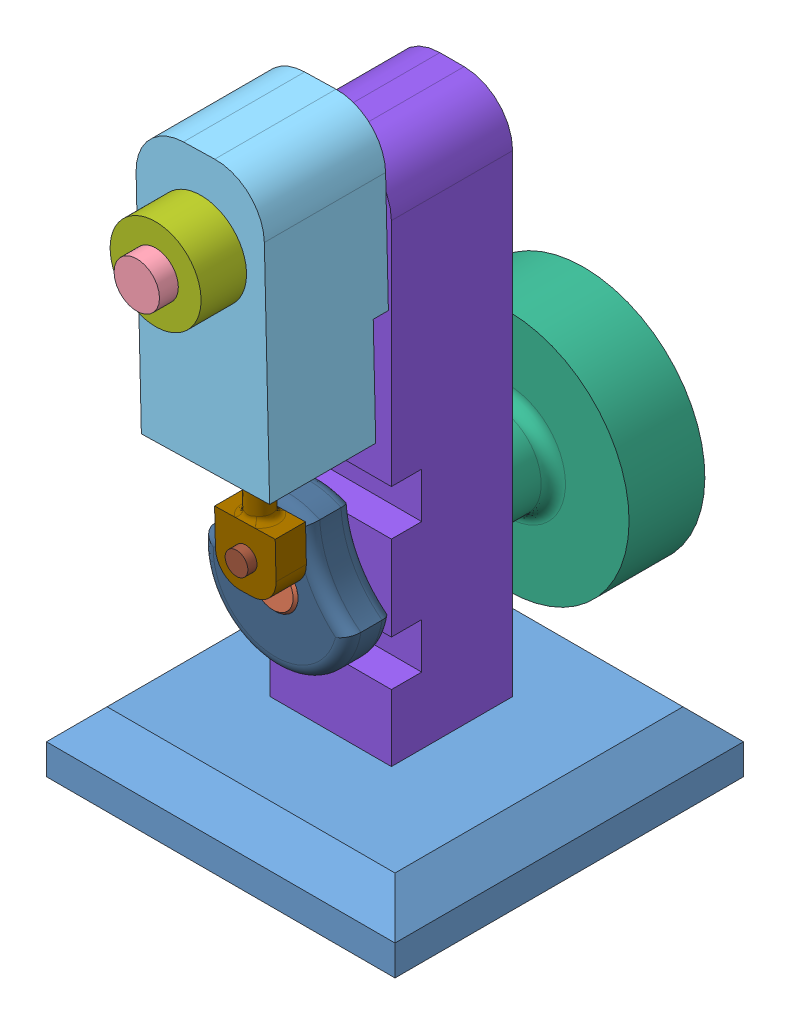
SolidWorks assembly Piston, configuration Default. Lengths in mm.
Overall size (2875 5329.59 4587.69).
11 component instances, 11 part files, 20 mates.
Components (placement in the parent):
- Part1_Base-1: Part1_Base [Default] at (2749.9801 1228.0338 658.172) size (2875 500 2875)
- Part1_Big Bar-1: Part1_Big Bar [Default] at (1225.0249 3003.0338 3015.4848) x (-0.109858 0.993947 0) z (-0.993947 -0.109858 0) size (375 2563 375)
- Part1_Bolt-1: Part1_Bolt [Default] at (1225.0249 1115.6147 2037.9848) x (0.905293 0 -0.424787) z (0.424787 0 0.905293) size (375 750 375)
- Part1_Connecting Bolt-1: Part1_Connecting Bolt [Default] at (1406.6994 5671.6591 4137.9848) x (0.824835 0.565374 0) z (-0.565374 0.824835 0) size (375 2250 375)
- Part1_Cylinder-1: Part1_Cylinder [Default] at (1649.1321 5484.5228 3607.9848) x (-0.999724 -0.023506 0) z (0.023506 -0.999724 0) size (1058.3 1000 2250)
- Part1_Fly Wheel-1: Part1_Fly Wheel [Default] at (1225.0249 3003.0338 452.4848) x (0.993947 0.109858 0) z (0.109858 -0.993947 0) size (2000 1000 2000)
- Part1_Holder-1: Part1_Holder [Default] at (1225.0249 5718.0338 3982.9848) x (0.933124 0.359555 0) z (0 0 1) size (750 750 500)
- Part1_Main Body-1: Part1_Main Body [Default] at (1725.0249 2291.4623 2303.3643) x (0 -0.473688 0.880693) z (0 -0.880693 -0.473688) size (2917.55 1000 4260.67)
- Part1_Piston-1: Part1_Piston [Default] at (1243.0245 4952.5149 3170.4848) x (0 0 -1) z (-0.999724 -0.023506 0) size (500 1835 500)
- Part1_Shaft Wheel-1: Part1_Shaft Wheel [Default] at (1225.0249 3003.0338 2620.4848) x (0.990355 -0.138553 0) z (-0.138553 -0.990355 0) size (1236.29 388.31 1222.98)
- Part1_Small Bar-1: Part1_Small Bar [Default] at (1280.1407 3373.9751 3370.4848) x (0.000458 1 0) z (-1 0.000458 0) size (187.5 750 187.5)
Mates (geometry in assembly coordinates):
- Coincident1: coincident: circle of Part1_Base-1; circle of Part1_Main Body-1
- Parallel1: parallel: line of Part1_Base-1 through (2499.9801 1728.0338 3283.172) axis (0 0 -1); line of Part1_Main Body-1 through (1725.0249 1728.0338 1537.9848) axis (0 0 1)
- Concentric1: concentric: cylinder of Part1_Big Bar-1 through (1225.0249 3003.0338 452.4848) axis (0 0 1) radius 187.5; cylinder of Part1_Main Body-1 through (1225.0249 3003.0338 -126.54) axis (0 0 1) radius 187.5
- Concentric2: concentric: cylinder of Part1_Big Bar-1 through (1225.0249 3003.0338 452.4848) axis (0 0 1) radius 187.5; cylinder of Part1_Fly Wheel-1 through (1225.0249 3003.0338 577.4848) axis (0 0 1) radius 187.5
- Parallel2: parallel: plane of Part1_Big Bar-1 through (1254.1239 3194.8918 577.4848) normal (-0.993947 -0.109858 0); plane of Part1_Fly Wheel-1 through (1272.8214 3008.3166 577.4848) normal (0.993947 0.109858 0)
- Coincident4: coincident: plane of Part1_Big Bar-1 through (1225.0249 3003.0338 452.4848) normal (0 0 -1); plane of Part1_Fly Wheel-1 through (1225.0249 3003.0338 452.4848) normal (0 0 -1)
- Concentric3: concentric: cylinder of Part1_Big Bar-1 through (1225.0249 3003.0338 452.4848) axis (0 0 1) radius 187.5; cylinder of Part1_Shaft Wheel-1 through (1225.0249 3003.0338 2995.4848) axis (0 0 -1) radius 187.5
- Concentric4: concentric: cylinder of Part1_Shaft Wheel-1 through (876.2224 2865.2948 2995.4848) axis (0 0 -1) radius 93.5; cylinder of Part1_Small Bar-1 through (876.2224 2865.2948 2620.4848) axis (0 0 1) radius 93.75
- Coincident6: coincident: plane of Part1_Shaft Wheel-1 through (1225.0249 3003.0338 2620.4848) normal (0 0 -1); plane of Part1_Small Bar-1 through (876.2224 2865.2948 2620.4848) normal (0 0 -1)
- Concentric5: concentric: cylinder of Part1_Piston-1 through (876.2224 2865.2948 2920.4838) axis (0 0 1) radius 93.5; cylinder of Part1_Small Bar-1 through (876.2224 2865.2948 2620.4848) axis (0 0 1) radius 93.75
- Distance1: distance = 50 mm: plane of Part1_Piston-1 through (1036.0864 3118.1675 3045.4848) normal (0 0 -1); plane of Part1_Shaft Wheel-1 through (1225.0249 3003.0338 2995.4848) normal (0 0 1)
- Coincident8: coincident: circle of Part1_Big Bar-1; plane of Part1_Shaft Wheel-1 through (1225.0249 3003.0338 2995.4848) normal (0 0 1)
- Concentric6: concentric: cylinder of Part1_Connecting Bolt-1 through (1225.0249 5718.0338 1887.9848) axis (0 0 1) radius 187.5; cylinder of Part1_Main Body-1 through (1225.0249 5718.0338 1887.9848) axis (0 0 1) radius 187.5
- Coincident9: coincident: plane of Part1_Connecting Bolt-1 through (1225.0249 5718.0338 1887.9848) normal (0 0 -1); plane of Part1_Main Body-1 through (1225.0249 5718.0338 1887.9848) normal (0 0 1)
- Concentric7: concentric: cylinder of Part1_Connecting Bolt-1 through (1225.0249 5718.0338 1887.9848) axis (0 0 1) radius 187.5; cylinder of Part1_Cylinder-1 through (1225.0249 5718.0338 3482.9848) axis (0 0 -1) radius 187.5
- Distance2: distance = 70 mm: plane of Part1_Cylinder-1 through (1649.1321 5484.5228 2607.9848) normal (0 0 -1); plane of Part1_Main Body-1 through (725.0249 3728.0338 2537.9848) normal (0 0 1)
- Concentric8: concentric: cylinder of Part1_Cylinder-1 through (1179.5735 5346.3021 3170.4848) axis (-0.121365 -0.992608 0) radius 250; cylinder of Part1_Piston-1 through (906.5638 3113.4468 3170.4848) axis (-0.121365 -0.992608 0) radius 250
- Concentric9: concentric: cylinder of Part1_Base-1 through (1225.0249 1728.0338 2037.9848) axis (0 1 0) radius 250; cylinder of Part1_Bolt-1 through (1225.0249 2005.1477 2037.9848) axis (0 -1 0) radius 125
- Concentric10: concentric: cylinder of Part1_Connecting Bolt-1 through (1225.0249 5718.0338 1887.9848) axis (0 0 1) radius 187.5; cylinder of Part1_Holder-1 through (1225.0249 5718.0338 3415.6599) axis (0 0 -1) radius 187.5
- Coincident11: coincident: plane of Part1_Cylinder-1 through (1610.89 5425.6258 3607.9848) normal (0 0 1); plane of Part1_Holder-1 through (875.1035 5583.2005 3607.9848) normal (0 0 -1)
